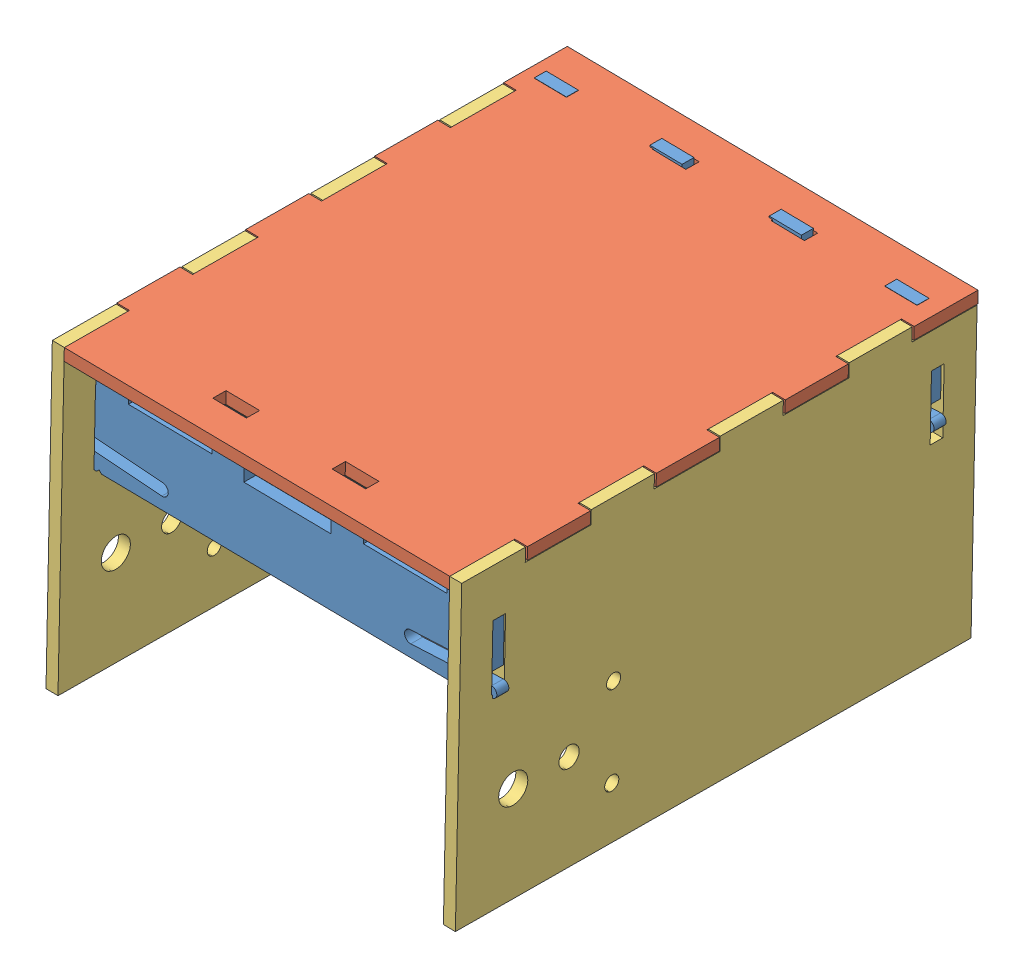
SolidWorks assembly chassis2a, configuration Default. Lengths in mm.
Overall size (83.68 61.46 102.01).
5 component instances, 3 part files, 14 mates.
Components (placement in the parent):
- crossbrace-1: crossbrace [Default] at (-21.7747 -21.0779 37.5946) x (0.999902 -0.013992 0.000048) z (-0.013992 -0.999878 0.006872) size (82.98 2.36 21.81)
- top_lasercut_2-1: top_lasercut_2 [Default] at (-97.7161 1.756 46.1538) x (0.999902 -0.013992 0.000048) z (0.000048 0.006872 0.999976) size (80.92 2.36 101.6)
- SidePanel_lasercut_2-1: SidePanel_lasercut_2 [Default] at (-22.4519 -56.5785 46.551) x (0.999902 -0.013992 0.000048) z (0.000048 0.006872 0.999976) size (2.36 59.64 101.6)
- SidePanel_lasercut_2-2: SidePanel_lasercut_2 [Default] at (-100.7525 -55.4828 46.5473) x (0.999902 -0.013992 0.000048) z (0.000048 0.006872 0.999976) size (2.36 59.64 101.6)
- crossbrace-2: crossbrace [Default] at (-22.1774 -19.1341 -48.9585) x (0.999902 -0.013992 0.000048) z (-0.013992 -0.999878 0.006872) size (82.98 2.36 21.81)
Mates (geometry in assembly coordinates):
- Coincident1: coincident aligned: plane of top_lasercut_2-1 through (-97.683 4.1179 46.1375) normal (0.013992 0.999878 -0.006872); plane of SidePanel_lasercut_2-2 through (-97.5561 4.1161 46.1376) normal (0.013992 0.999878 -0.006872)
- Coincident2: coincident aligned: plane of top_lasercut_2-1 through (-97.683 4.1179 46.1375) normal (0.013992 0.999878 -0.006872); plane of SidePanel_lasercut_2-1 through (-19.2555 3.0204 46.1413) normal (0.013992 0.999878 -0.006872)
- Coincident3: coincident anti-aligned: plane of top_lasercut_2-1 through (-21.6505 0.6916 46.1574) normal (0.999902 -0.013992 0.000048); plane of SidePanel_lasercut_2-1 through (-22.4519 -56.5785 46.551) normal (-0.999902 0.013992 -0.000048)
- Coincident4: coincident aligned: plane of top_lasercut_2-1 through (-97.683 4.1179 46.1375) normal (0.000048 0.006872 0.999976); plane of SidePanel_lasercut_2-1 through (-20.09 -56.6115 46.5512) normal (0.000048 0.006872 0.999976)
- Coincident5: coincident aligned: plane of top_lasercut_2-1 through (-97.683 4.1179 46.1375) normal (0.000048 0.006872 0.999976); plane of SidePanel_lasercut_2-2 through (-98.3905 -55.5158 46.5474) normal (0.000048 0.006872 0.999976)
- Coincident6: coincident anti-aligned: plane of top_lasercut_2-1 through (-97.5891 1.7542 46.1538) normal (-0.999902 0.013992 -0.000048); plane of SidePanel_lasercut_2-2 through (-98.3905 -55.5158 46.5474) normal (0.999902 -0.013992 0.000048)
- Coincident8: coincident anti-aligned: plane of crossbrace-1 through (-19.5487 -18.7449 39.9408) normal (0.000048 0.006872 0.999976); plane of SidePanel_lasercut_2-1 through (-21.7511 -6.514 39.8568) normal (-0.000048 -0.006872 -0.999976)
- Coincident9: coincident: plane of crossbrace-1 through (-19.2908 0.4649 36.4534) normal (-0.999902 0.013992 -0.000048); plane of SidePanel_lasercut_2-1 through (-20.0901 -56.6346 43.196) normal (0.999902 -0.013992 0.000048)
- Coincident10: coincident: plane of crossbrace-1 through (-97.4358 -5.478 36.498) normal (0.013992 0.999878 -0.006872); plane of SidePanel_lasercut_2-2 through (-100.0518 -5.4414 36.4979) normal (-0.013992 -0.999878 0.006872)
- Coincident11: coincident anti-aligned: plane of SidePanel_lasercut_2-2 through (-100.0559 -6.0292 -49.0449) normal (0.000048 0.006872 0.999976); plane of crossbrace-2 through (-19.9515 -16.8173 -48.9746) normal (-0.000048 -0.006872 -0.999976)
- Coincident12: coincident: plane of SidePanel_lasercut_2-2 through (-100.7526 -55.5059 43.1921) normal (-0.999902 0.013992 -0.000048); plane of crossbrace-2 through (-99.9575 0.9989 -50.0862) normal (0.999902 -0.013992 0.000048)
- Coincident13: coincident: plane of SidePanel_lasercut_2-2 through (-100.056 -6.0523 -52.4) normal (-0.013992 -0.999878 0.006872); plane of crossbrace-2 through (-97.44 -6.0727 -50.0378) normal (0.013992 0.999878 -0.006872)
- Coincident15: coincident anti-aligned: plane of crossbrace-1 through (-97.5626 -5.4531 39.8532) normal (0.013992 0.999878 -0.006872); plane of SidePanel_lasercut_2-2 through (-100.0516 -5.4183 39.853) normal (-0.013992 -0.999878 0.006872)
- Coincident16: coincident anti-aligned: plane of crossbrace-1 through (-74.7811 -5.7719 39.8543) normal (-0.999902 0.013992 -0.000048); plane of top_lasercut_2-1 through (-74.6478 3.7519 39.7888) normal (0.999902 -0.013992 0.000048)
